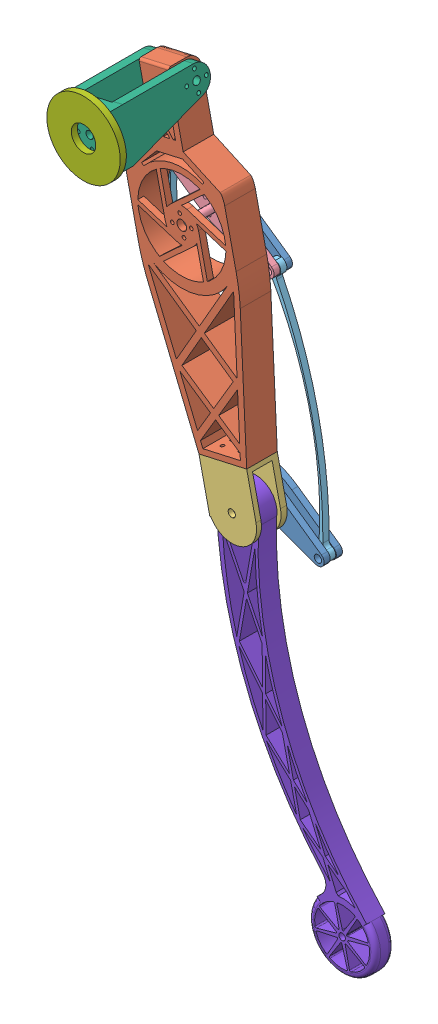
SolidWorks assembly quadbot_leg, configuration Domyślna. Lengths in mm.
Overall size (223.82 596.83 102.79).
11 component instances, 8 part files, 32 mates.
Components (placement in the parent):
- muscle_trailer-1: muscle_trailer [Domyślna] at (-14.0192 -180.5779 -87.4423) x (-0.888375 0.459117 -0.000966) z (-0.000329 0.001467 0.999999) size (110.2 22.37 5)
- femur_part-1: femur_part [Domyślna] at (-32.5666 -100.278 -56.5662) x (-0.975694 -0.219136 0) z (0.219136 -0.975693 0.001504) size (82 25 260)
- elbow_joint-1: elbow_joint [Domyślna] at (-28.888 -205.6424 -60.4104) x (0.000329 -0.001467 -0.999999) z (0.975694 0.219136 0) size (25 55 40)
- motor_trailer-1: motor_trailer [Domyślna] at (-55.1647 2.6206 -87.7247) x (-0.888375 0.459117 -0.000966) z (-0.000329 0.001467 0.999999) size (110.2 22.37 25)
- muscle_spring-1: muscle_spring [Domyślna] at (-58.4363 -157.6294 -92.4907) x (-0.219136 0.975693 -0.001504) z (-0.000329 0.001467 0.999999) size (197.19 16.34 5)
- muscle_spring-2: muscle_spring [Domyślna] at (30.3996 -203.5338 -87.394) x (-0.219136 0.975693 -0.001504) z (0.000329 -0.001467 -0.999999) size (197.19 16.34 5)
- shoulder_part_1-1: shoulder_part_1 [Domyślna] at (-78.2097 105.2275 0) x (-0.975694 -0.219136 0) z (0.219136 -0.975694 0) size (42 80 40)
- body_plate-1: body_plate [Domyślna] at (-73.827 85.7136 -7.4722) x (-0.990586 0.13689 0) z (0.13689 0.990586 0) size (60 5 60)
- tibia_part-1: tibia_part [Domyślna] at (3.3661 -176.2076 -60.943) x (0.000329 -0.001467 -0.999999) z (-0.241637 0.970366 -0.001503) size (15 73.75 317.01)
- muscle_trailer-2: muscle_trailer [Domyślna] at (-14.0159 -180.5926 -97.4423) x (-0.888375 0.459117 -0.000966) z (-0.000329 0.001467 0.999999) size (110.2 22.37 5)
- muscle_trailer-4: muscle_trailer [Domyślna] at (-55.1614 2.6059 -97.7246) x (-0.888375 0.459117 -0.000966) z (-0.000329 0.001467 0.999999) size (110.2 22.37 5)
Mates (geometry in assembly coordinates):
- Koncentryczne1: concentric aligned: circle of ?; circle of muscle_trailer-1
- Koncentryczne2: concentric anti-aligned: cylinder of ? through (-282.0654 81.1741 -87.0775) axis (-0.050193 0.006382 0.998719) radius 3; cylinder of elbow_joint-1 through (-283.0693 81.3017 -67.1031) axis (0.050193 -0.006382 -0.998719) radius 3
- Prostopadle2: perpendicular: plane of ? through (-270.8954 98.0347 -86.6239) normal (0.060118 0.998186 -0.003357); plane of muscle_trailer-1
- Odległość1: distance = 1 mm anti-aligned: plane of muscle_trailer-1 through (-58.4396 -157.6147 -82.4907) normal (-0.000329 0.001467 0.999999); plane of elbow_joint-1 through (-1.9058 -143.2446 -81.4931) normal (0.000329 -0.001467 -0.999999)
- Wspólnie26: coincident aligned: plane of muscle_trailer-1 through (-58.4379 -157.622 -87.4907) normal (0.000329 -0.001467 -0.999999); plane of motor_trailer-1 through (-99.5835 25.5764 -87.773) normal (0.000329 -0.001467 -0.999999)
- Równolegle4: parallel aligned: plane of muscle_trailer-1; plane of motor_trailer-1
- Koncentryczne4: concentric aligned: cylinder of muscle_trailer-1 through (-58.4396 -157.6147 -82.4907) axis (0.000329 -0.001467 -0.999999) radius 3; cylinder of muscle_spring-1 through (-58.4379 -157.622 -87.4907) axis (0.000329 -0.001467 -0.999999) radius 3
- Koncentryczne5: concentric aligned: cylinder of motor_trailer-1 through (-99.5851 25.5838 -82.773) axis (0.000329 -0.001467 -0.999999) radius 3; cylinder of muscle_spring-1 through (-99.5835 25.5764 -87.773) axis (0.000329 -0.001467 -0.999999) radius 3
- Koncentryczne6: concentric anti-aligned: cylinder of motor_trailer-1 through (-10.7476 -20.328 -82.6763) axis (0.000329 -0.001467 -0.999999) radius 3; cylinder of muscle_spring-2 through (-10.7443 -20.3426 -92.6763) axis (-0.000329 0.001467 0.999999) radius 3
- Wspólnie27: coincident anti-aligned: plane of motor_trailer-1 through (-99.5835 25.5764 -87.773) normal (0.000329 -0.001467 -0.999999); plane of muscle_spring-2 through (-121.9891 -190.3917 -87.4635) normal (-0.000329 0.001467 0.999999)
- Koncentryczne7: concentric anti-aligned: cylinder of muscle_trailer-1 through (30.3979 -203.5264 -82.394) axis (0.000329 -0.001467 -0.999999) radius 3; cylinder of muscle_spring-2 through (30.4012 -203.5411 -92.394) axis (-0.000329 0.001467 0.999999) radius 3
- Wspólnie28: coincident anti-aligned: plane of muscle_trailer-1 through (-58.4379 -157.622 -87.4907) normal (0.000329 -0.001467 -0.999999); plane of muscle_spring-1 through (73.6953 -80.5776 -87.5601) normal (-0.000329 0.001467 0.999999)
- Koncentryczne8: concentric anti-aligned: cylinder of femur_part-1 through (-113.8219 85.8173 -68.866) axis (0.975694 0.219136 0) radius 3; cylinder of shoulder_part_1-1 through (-55.2802 98.9655 -68.866) axis (-0.975694 -0.219136 0) radius 3
- Odległość2: distance = 0.5 mm anti-aligned: plane of femur_part-1 through (-19.881 -97.4365 -61.5662) normal (0.975694 0.219136 0); plane of shoulder_part_1-1 through (-56.7603 69.0485 -10) normal (-0.975694 -0.219136 0)
- Wspólnie31: coincident anti-aligned: plane of body_plate-1 through (-63.9212 84.3447 0) normal (0 0 -1); plane of assembly through (0 0 0) normal (0 0 1)
- Koncentryczne9: concentric aligned: cylinder of shoulder_part_1-1 through (-73.827 85.7136 0) axis (0 0 -1) radius 3; cylinder of body_plate-1 through (-73.827 85.7136 -7.4722) axis (0 0 -1) radius 10
- Wspólnie32: coincident anti-aligned: plane of shoulder_part_1-1 through (-48.9547 70.8016 0) normal (0 0 1); plane of body_plate-1 through (-63.9212 84.3447 0) normal (0 0 -1)
- Koncentryczne10: concentric anti-aligned: cylinder of elbow_joint-1 through (-14.0294 -180.5324 -56.4424) axis (0.000329 -0.001467 -0.999999) radius 3; cylinder of tibia_part-1 through (-14.023 -180.561 -75.9424) axis (-0.000329 0.001467 0.999999) radius 3
- Odległość3: distance = 0.5 mm anti-aligned: plane of tibia_part-1 through (3.3711 -176.2296 -75.943) normal (0.000329 -0.001467 -0.999999); plane of elbow_joint-1 through (10.145 -196.9004 -76.4104) normal (-0.000329 0.001467 0.999999)
- Kąt2: planar angle = 2.420538 rad aligned: plane of muscle_trailer-1; plane of tibia_part-1 through (3.3661 -176.2076 -60.943) normal (-0.241637 0.970366 -0.001503)
- Koncentryczne11: concentric aligned: cylinder of muscle_trailer-1 through (-14.0208 -180.5706 -82.4424) axis (0.000329 -0.001467 -0.999999) radius 3; cylinder of elbow_joint-1 through (-14.0294 -180.5324 -56.4424) axis (0.000329 -0.001467 -0.999999) radius 3
- Wspólnie40: coincident anti-aligned: line of femur_part-1 through (-40.9336 -152.0101 -81.4931) axis (0.975694 0.219136 0); line of elbow_joint-1 through (-1.9058 -143.2446 -81.4931) axis (-0.975694 -0.219136 0)
- Wspólnie41: coincident aligned: line of femur_part-1 through (-1.9058 -143.2446 -81.4931) axis (-0.000329 0.001467 0.999999); line of elbow_joint-1 through (-1.9058 -143.2446 -81.4931) axis (-0.000329 0.001467 0.999999)
- Koncentryczne12: concentric anti-aligned: cylinder of femur_part-1 through (-55.1733 2.6587 -61.7247) axis (-0.000329 0.001467 0.999999) radius 4; cylinder of motor_trailer-1 through (-55.173 2.6573 -62.7247) axis (0.000329 -0.001467 -0.999999) radius 3
- Koncentryczne13: concentric aligned: cylinder of muscle_trailer-1 through (-14.0208 -180.5706 -82.4424) axis (0.000329 -0.001467 -0.999999) radius 3; cylinder of muscle_trailer-2 through (-14.0175 -180.5852 -92.4423) axis (0.000329 -0.001467 -0.999999) radius 3
- Odległość4: distance = 5 mm anti-aligned: plane of muscle_trailer-2 through (-58.4363 -157.6294 -92.4907) normal (-0.000329 0.001467 0.999999); plane of muscle_trailer-1 through (-58.4379 -157.622 -87.4907) normal (0.000329 -0.001467 -0.999999)
- Koncentryczne14: concentric aligned: cylinder of muscle_spring-1 through (-58.4379 -157.622 -87.4907) axis (0.000329 -0.001467 -0.999999) radius 3; cylinder of muscle_trailer-2 through (-58.4363 -157.6294 -92.4907) axis (0.000329 -0.001467 -0.999999) radius 3
- Koncentryczne15: concentric anti-aligned: cylinder of motor_trailer-1 through (-111.5796 -8.8696 -60.1416) axis (-0.017376 -0.027431 -0.999473) radius 3; circle of ?
- Wspólnie44: coincident: plane of motor_trailer-1; plane of ?
- Koncentryczne16: concentric aligned: cylinder of motor_trailer-1 through (-55.173 2.6573 -62.7247) axis (0.000329 -0.001467 -0.999999) radius 3; cylinder of muscle_trailer-4 through (-55.1631 2.6132 -92.7246) axis (0.000329 -0.001467 -0.999999) radius 3
- Równolegle5: parallel aligned: plane of motor_trailer-1; plane of muscle_trailer-4
- Odległość5: distance = 5 mm anti-aligned: plane of motor_trailer-1 through (-99.5835 25.5764 -87.773) normal (0.000329 -0.001467 -0.999999); plane of muscle_trailer-4 through (-99.5818 25.5691 -92.773) normal (-0.000329 0.001467 0.999999)
